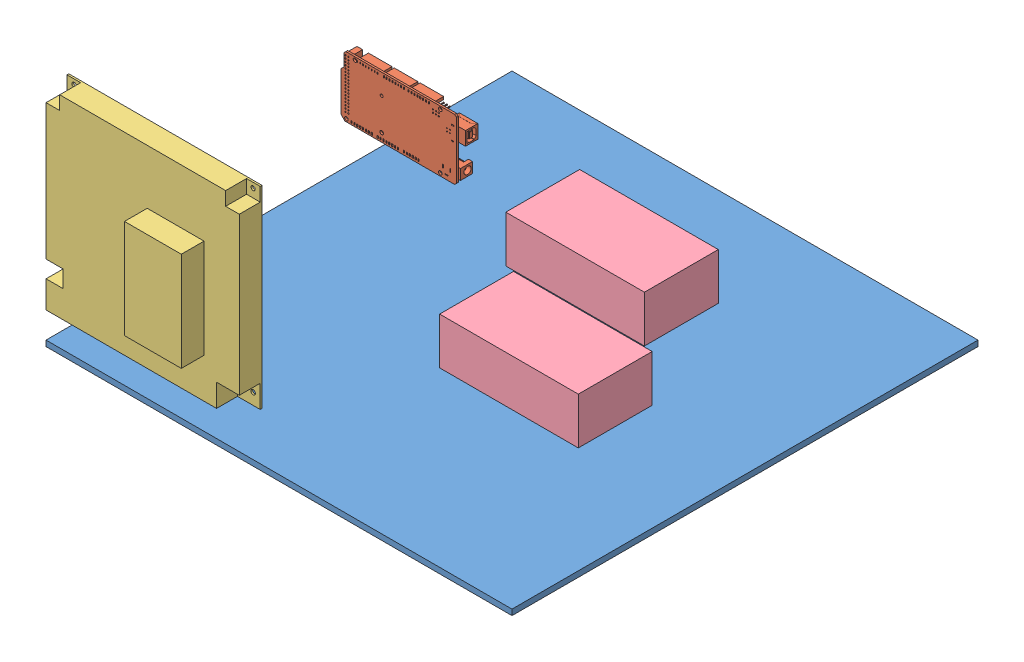
SolidWorks assembly 組合件1, configuration 預設. Lengths in mm.
Overall size (410 331.16 562.34).
6 component instances, 5 part files, 0 mates.
Components (placement in the parent):
- 底板-1: 底板 [預設] at (-15.7008 -15.3887 410) size (410 5 410)
- ArduinoMega-1: ArduinoMega [Default] at (-138.0777 86.9877 385.6944) size (107.95 53.42 12.95)
- TX2-1: TX2 [預設] at (-3.2966 229.8781 727.344) size (170 170 40)
- 電池-1: 電池 [預設] at (102.0049 56.936 497.865) size (122 41 65)
- 緊急按鈕-1: 緊急按鈕 [預設] at (-161.4232 -16.2838 565.1873) size (39 73 29)
- 電池-2: 電池 [預設] at (99.8066 103.3274 437.5025) size (122 41 65)
